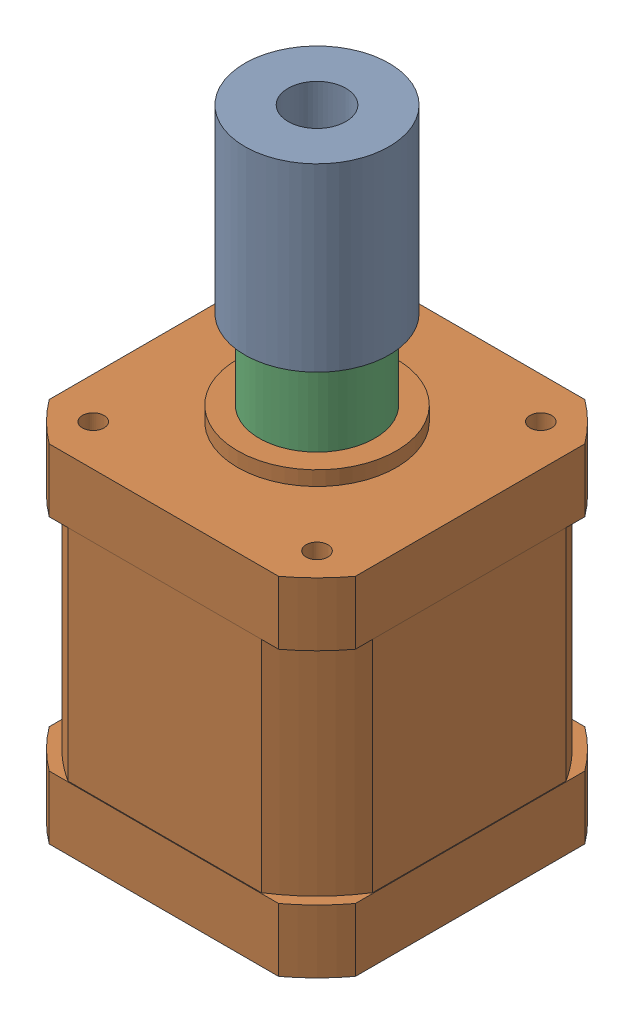
SolidWorks assembly z_motor_thrust_coupling_assembly_2, configuration Default. Lengths in mm.
Overall size (42.42 86 42.42).
4 component instances, 4 part files, 0 mates.
Components (placement in the parent):
- plumb_coupling_8mm_to_5mm-1: plumb_coupling_8mm_to_5mm [Default] at (304.071 41.773 434.2083) x (0.979819 0 -0.199886) z (0.199886 0 0.979819) size (20 25 20)
- 17HM19-2004S-1: 17HM19-2004S [Default] at (304.071 28.773 434.2083) x (0 0 -1) z (0 1 0) size (42.42 42.42 72)
- z_thrust_bearing_spacer_Z Thrust Bearing Spacer-1: z_thrust_bearing_spacer_Z Thrust Bearing Spacer [Default] at (304.071 30.773 434.2083) x (0.992689 0 -0.120701) z (0.120701 0 0.992689) size (16 10.8 16)
- m5_shim_0.2mm_thick_98089A246_98089A246-1: m5_shim_0.2mm_thick_98089A246_98089A246 [Default] at (304.071 41.573 434.2083) x (0.943035 0 -0.332694) z (0.332694 0 0.943035) size (10 0.2 10)
